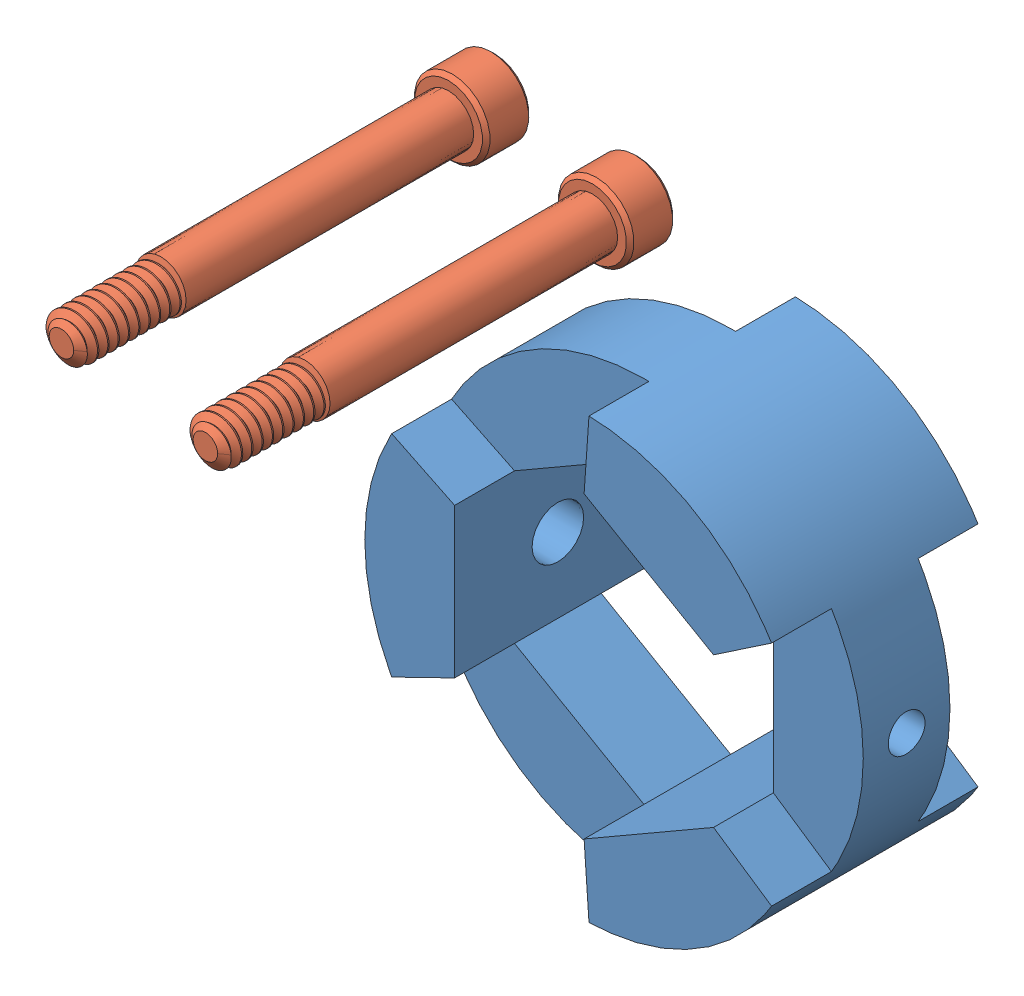
SolidWorks assembly 217-3628-STEP, configuration Default. Lengths in mm.
Overall size (36.08 28.85 28.93).
3 component instances, 2 part files, 0 mates.
Components (placement in the parent):
- 217-3423-009 Rev3_1-1: 217-3423-009 Rev3_1 [Default] at origin size (26.99 26.99 12.7)
- 217-3423-014 Rev1_1-1: 217-3423-014 Rev1_1 [Default] at (-20.2612 13.0312 18.2417) size (4.65 4.65 26.79)
- 217-3423-014 Rev1_1-2: 217-3423-014 Rev1_1 [Default] at (-13.5411 9.8211 16.106) size (4.65 4.65 26.79)
